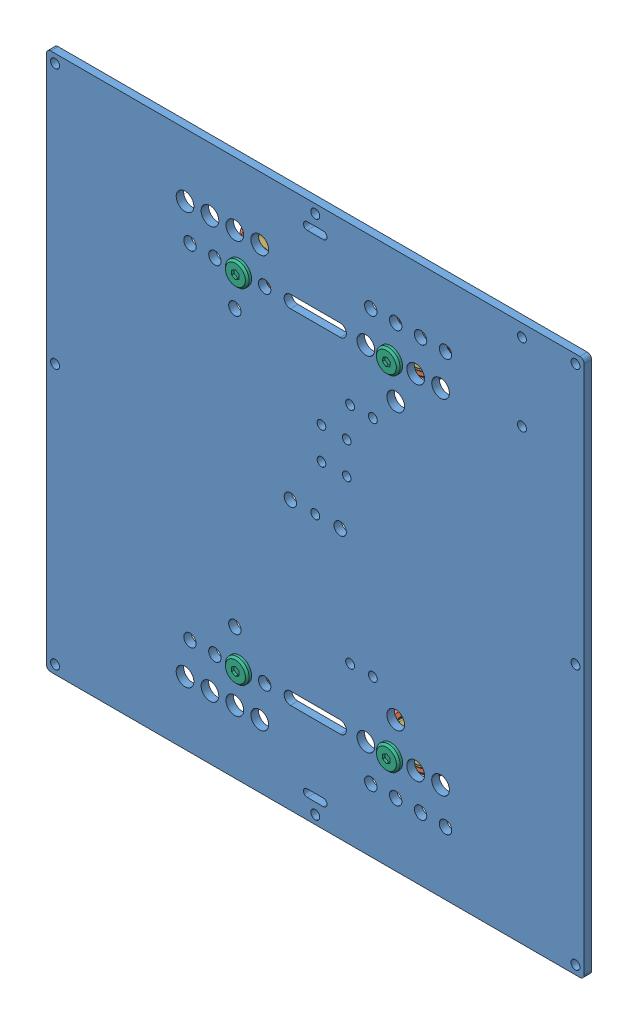
SolidWorks assembly Universal Build Plate with Delrin V-Wheels for 40mm V-Slot, configuration Default. Lengths in mm.
Overall size (216 216 27.2).
33 component instances, 7 part files, 7 mates.
Components (placement in the parent):
- V-Slot Universal Build Plate-1: V-Slot Universal Build Plate [Default] at (-53.2124 10.1898 21.1567) size (216 216 3)
- V-Slot Delrin Dual Wheel Assembly-1: V-Slot Delrin Dual Wheel Assembly [Default] at (-87.7089 66.118 18.8913) size (23.89 23.89 27.2)
  - Delrin Dual V-Wheel-1: Delrin Dual V-Wheel [Default] at (4.1766 13.0717 -11.0846) size (23.89 23.89 10.23)
  - Precision Ball Bearing-1: Precision Ball Bearing [Default] at (4.1766 13.0717 -8.0846) x (0 0 -1) z (1 0 0) size (5 16 16)
  - Precision Ball Bearing-2: Precision Ball Bearing [Default] at (4.1766 13.0717 -14.0846) x (0 0 -1) z (1 0 0) size (5 16 16)
  - 5mm Precision Washer-1: 5mm Precision Washer [Default] at (4.1766 13.0717 -11.5846) x (0 0 1) z (-1 0 0) size (1 10 10)
  - .25 Inch Aluminum Spacer-1: .25 Inch Aluminum Spacer [Default] at (4.1766 13.0717 0.7654) x (0 0 -1) z (1 0 0) size (6.35 8 8)
  - 5mm Low Profile Socket Head Screw - Multiple Lengths-1: 5mm Low Profile Socket Head Screw - Multiple Lengths [Default] at (4.1766 13.0717 5.5154) x (0 0 -1) z (1 0 0) size (27.2 9.5 9.5)
  - Nylon Insert Hex Locknut 5mm-1: Nylon Insert Hex Locknut 5mm [Default] at (4.1766 13.0717 -16.5846) x (-0.923728 -0.383049 0) z (0 0 -1) size (7.68 8.82 4.5)
- V-Slot Delrin Dual Wheel Assembly-2: V-Slot Delrin Dual Wheel Assembly [Default] at (-87.7089 -71.882 18.8913) size (23.89 23.89 27.2)
  - Delrin Dual V-Wheel-1: Delrin Dual V-Wheel [Default] at (4.1766 13.0717 -11.0846) size (23.89 23.89 10.23)
  - Precision Ball Bearing-1: Precision Ball Bearing [Default] at (4.1766 13.0717 -8.0846) x (0 0 -1) z (1 0 0) size (5 16 16)
  - Precision Ball Bearing-2: Precision Ball Bearing [Default] at (4.1766 13.0717 -14.0846) x (0 0 -1) z (1 0 0) size (5 16 16)
  - 5mm Precision Washer-1: 5mm Precision Washer [Default] at (4.1766 13.0717 -11.5846) x (0 0 1) z (-1 0 0) size (1 10 10)
  - .25 Inch Aluminum Spacer-1: .25 Inch Aluminum Spacer [Default] at (4.1766 13.0717 0.7654) x (0 0 -1) z (1 0 0) size (6.35 8 8)
  - 5mm Low Profile Socket Head Screw - Multiple Lengths-1: 5mm Low Profile Socket Head Screw - Multiple Lengths [Default] at (4.1766 13.0717 5.5154) x (0 0 -1) z (1 0 0) size (27.2 9.5 9.5)
  - Nylon Insert Hex Locknut 5mm-1: Nylon Insert Hex Locknut 5mm [Default] at (4.1766 13.0717 -16.5846) x (-0.923728 -0.383049 0) z (0 0 -1) size (7.68 8.82 4.5)
- V-Slot Delrin Dual Wheel Assembly-3: V-Slot Delrin Dual Wheel Assembly [Default] at (-15.3542 67.7229 18.8913) x (0.62878 0.777583 0) z (0 0 1) size (23.89 23.89 27.2)
  - Delrin Dual V-Wheel-1: Delrin Dual V-Wheel [Default] at (4.1766 13.0717 -11.0846) size (23.89 23.89 10.23)
  - Precision Ball Bearing-1: Precision Ball Bearing [Default] at (4.1766 13.0717 -8.0846) x (0 0 -1) z (1 0 0) size (5 16 16)
  - Precision Ball Bearing-2: Precision Ball Bearing [Default] at (4.1766 13.0717 -14.0846) x (0 0 -1) z (1 0 0) size (5 16 16)
  - 5mm Precision Washer-1: 5mm Precision Washer [Default] at (4.1766 13.0717 -11.5846) x (0 0 1) z (-1 0 0) size (1 10 10)
  - .25 Inch Aluminum Spacer-1: .25 Inch Aluminum Spacer [Default] at (4.1766 13.0717 0.7654) x (0 0 -1) z (1 0 0) size (6.35 8 8)
  - 5mm Low Profile Socket Head Screw - Multiple Lengths-1: 5mm Low Profile Socket Head Screw - Multiple Lengths [Default] at (4.1766 13.0717 5.5154) x (0 0 -1) z (1 0 0) size (27.2 9.5 9.5)
  - Nylon Insert Hex Locknut 5mm-1: Nylon Insert Hex Locknut 5mm [Default] at (4.1766 13.0717 -16.5846) x (-0.923728 -0.383049 0) z (0 0 -1) size (7.68 8.82 4.5)
- V-Slot Delrin Dual Wheel Assembly-4: V-Slot Delrin Dual Wheel Assembly [Default] at (-27.0689 -71.882 18.8913) size (23.89 23.89 27.2)
  - Delrin Dual V-Wheel-1: Delrin Dual V-Wheel [Default] at (4.1766 13.0717 -11.0846) size (23.89 23.89 10.23)
  - Precision Ball Bearing-1: Precision Ball Bearing [Default] at (4.1766 13.0717 -8.0846) x (0 0 -1) z (1 0 0) size (5 16 16)
  - Precision Ball Bearing-2: Precision Ball Bearing [Default] at (4.1766 13.0717 -14.0846) x (0 0 -1) z (1 0 0) size (5 16 16)
  - 5mm Precision Washer-1: 5mm Precision Washer [Default] at (4.1766 13.0717 -11.5846) x (0 0 1) z (-1 0 0) size (1 10 10)
  - .25 Inch Aluminum Spacer-1: .25 Inch Aluminum Spacer [Default] at (4.1766 13.0717 0.7654) x (0 0 -1) z (1 0 0) size (6.35 8 8)
  - 5mm Low Profile Socket Head Screw - Multiple Lengths-1: 5mm Low Profile Socket Head Screw - Multiple Lengths [Default] at (4.1766 13.0717 5.5154) x (0 0 -1) z (1 0 0) size (27.2 9.5 9.5)
  - Nylon Insert Hex Locknut 5mm-1: Nylon Insert Hex Locknut 5mm [Default] at (4.1766 13.0717 -16.5846) x (-0.923728 -0.383049 0) z (0 0 -1) size (7.68 8.82 4.5)
Mates (geometry in assembly coordinates):
- Coincident1: coincident: plane of V-Slot Universal Build Plate-1 through (-159.4624 -96.0602 22.6567) normal (0 0 1); plane of V-Slot Delrin Dual Wheel Assembly-3/5mm Low Profile Socket Head Screw - Multiple Lengths-1 through (84.7108 40.3829 22.6567) normal (0 0 -1)
- Coincident2: coincident anti-aligned: plane of V-Slot Universal Build Plate-1 through (-159.4624 -96.0602 22.6567) normal (0 0 1); plane of V-Slot Delrin Dual Wheel Assembly-4/5mm Low Profile Socket Head Screw - Multiple Lengths-1 through (-22.8924 -56.3102 22.6567) normal (0 0 -1)
- Coincident3: coincident anti-aligned: plane of V-Slot Universal Build Plate-1 through (-159.4624 -96.0602 22.6567) normal (0 0 1); plane of V-Slot Delrin Dual Wheel Assembly-1/5mm Low Profile Socket Head Screw - Multiple Lengths-1 through (-83.5324 81.6898 22.6567) normal (0 0 -1)
- Coincident4: coincident anti-aligned: plane of V-Slot Universal Build Plate-1 through (-159.4624 -96.0602 22.6567) normal (0 0 1); plane of V-Slot Delrin Dual Wheel Assembly-2/5mm Low Profile Socket Head Screw - Multiple Lengths-1 through (-83.5324 -56.3102 22.6567) normal (0 0 -1)
- Concentric3: concentric anti-aligned: cylinder of V-Slot Universal Build Plate-1 through (-83.5324 -58.8102 22.6567) axis (0 0 -1) radius 2.5; cylinder of V-Slot Delrin Dual Wheel Assembly-2/.25 Inch Aluminum Spacer-1 through (-83.5324 -58.8102 13.3067) axis (0 0 1) radius 4
- Concentric4: concentric anti-aligned: cylinder of V-Slot Universal Build Plate-1 through (-83.5324 79.1898 22.6567) axis (0 0 -1) radius 2.5; cylinder of V-Slot Delrin Dual Wheel Assembly-1/.25 Inch Aluminum Spacer-1 through (-83.5324 79.1898 13.3067) axis (0 0 1) radius 4
- Concentric5: concentric anti-aligned: cylinder of V-Slot Universal Build Plate-1 through (-22.8924 79.1898 22.6567) axis (0 0 -1) radius 3.57; cylinder of V-Slot Delrin Dual Wheel Assembly-3/.25 Inch Aluminum Spacer-1 through (-22.8924 79.1898 13.3067) axis (0 0 1) radius 4
